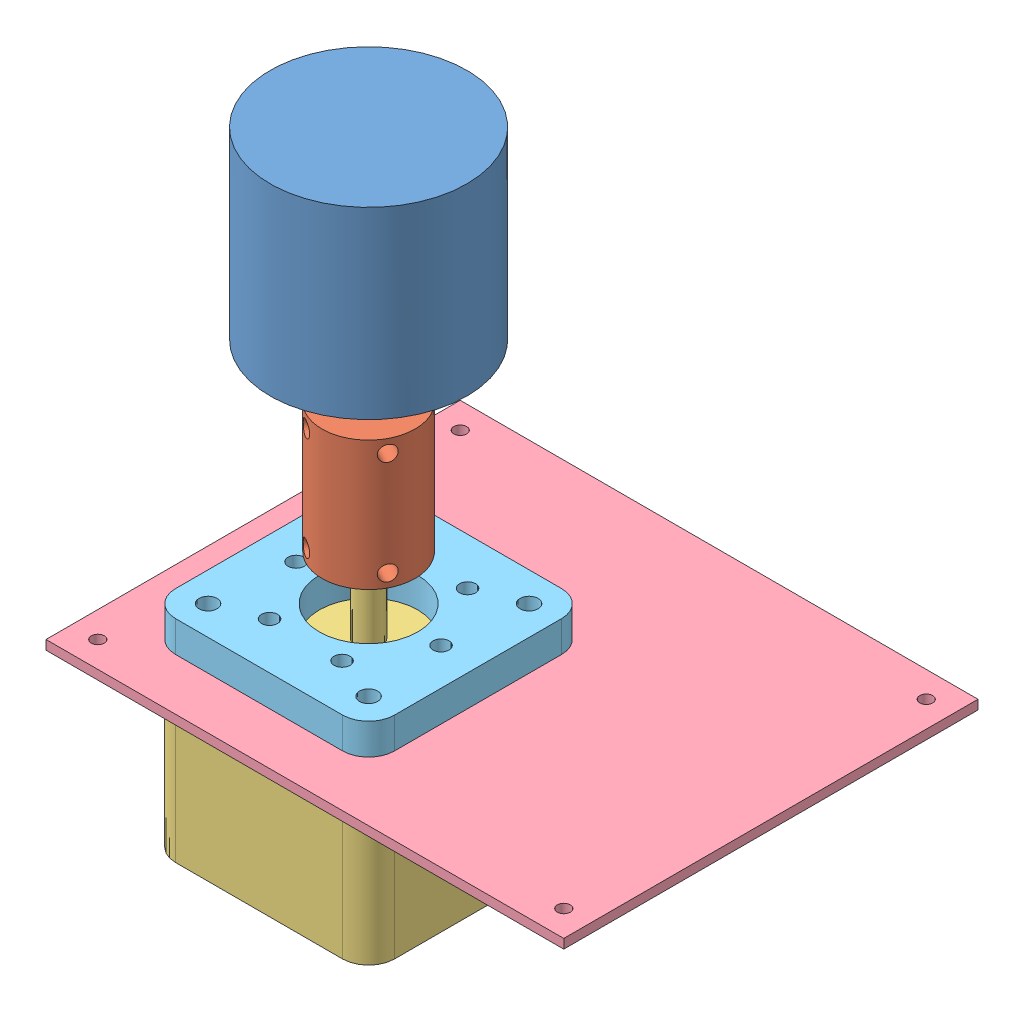
SolidWorks assembly Test Fixture, configuration Default. Lengths in mm.
Overall size (100 120.5 80).
5 component instances, 5 part files, 13 mates.
Components (placement in the parent):
- Optical-Encoder-1: Optical-Encoder [Default] at (21.15 52 -21.15) x (1 0 0) z (0 -1 0) size (38 38 53.5)
- flexible-coupling-1: flexible-coupling [Default] at (21.15 29 -21.15) x (0.884065 0 0.467364) z (0 -1 0) size (18 18 25)
- nema17-1: nema17 [Default] at (21.15 -16.5 -21.15) x (0 0 -1) z (0 1 0) size (42.3 42.3 57)
- test-fixture-pcb-1: test-fixture-pcb [Default] at (40 0 -30) size (100 1.8 80)
- motor-mount-1: motor-mount [Default] at (21.15 4.8 -21.15) x (0 0 -1) z (-1 0 0) size (42.3 6 42.3)
Mates (geometry in assembly coordinates):
- Concentric1: concentric aligned: circle of Optical-Encoder-1; circle of flexible-coupling-1
- Concentric2: concentric anti-aligned: circle of flexible-coupling-1; circle of nema17-1
- Distance4: distance = 7.5 mm anti-aligned: plane of nema17-1 through (21.15 24 -21.15) normal (0 1 0); plane of flexible-coupling-1 through (21.15 16.5 -21.15) normal (0 -1 0)
- Distance6: distance = 7.5 mm anti-aligned: plane of Optical-Encoder-1 through (21.15 34 -21.15) normal (0 -1 0); plane of flexible-coupling-1 through (21.15 41.5 -21.15) normal (0 1 0)
- Coincident8: coincident aligned: plane of nema17-1 through (37.3 0 -5) normal (0 1 0); plane of assembly through (0 0 0) normal (0 1 0)
- Coincident9: coincident anti-aligned: plane of nema17-1 through (0 0 -5) normal (-1 0 0); plane of assembly through (0 0 0) normal (1 0 0)
- Coincident10: coincident aligned: plane of nema17-1 through (37.3 0 0) normal (0 0 1); plane of assembly through (0 0 0) normal (0 0 1)
- Distance7: distance = 10 mm aligned: plane of test-fixture-pcb-1 through (-10 1.8 10) normal (-1 0 0); plane of nema17-1 through (0 0 -5) normal (-1 0 0)
- Distance8: distance = 10 mm aligned: plane of test-fixture-pcb-1 through (-10 1.8 10) normal (0 0 1); plane of nema17-1 through (37.3 0 0) normal (0 0 1)
- Concentric3: concentric aligned: circle of nema17-1; circle of motor-mount-1
- Concentric4: concentric aligned: circle of nema17-1; circle of motor-mount-1
- Coincident11: coincident anti-aligned: plane of nema17-1 through (37.3 0 -5) normal (0 1 0); plane of test-fixture-pcb-1 through (40 0 -30) normal (0 -1 0)
- Coincident13: coincident anti-aligned: plane of test-fixture-pcb-1 through (40 1.8 -30) normal (0 1 0); plane of motor-mount-1 through (21.15 1.8 -21.15) normal (0 -1 0)
